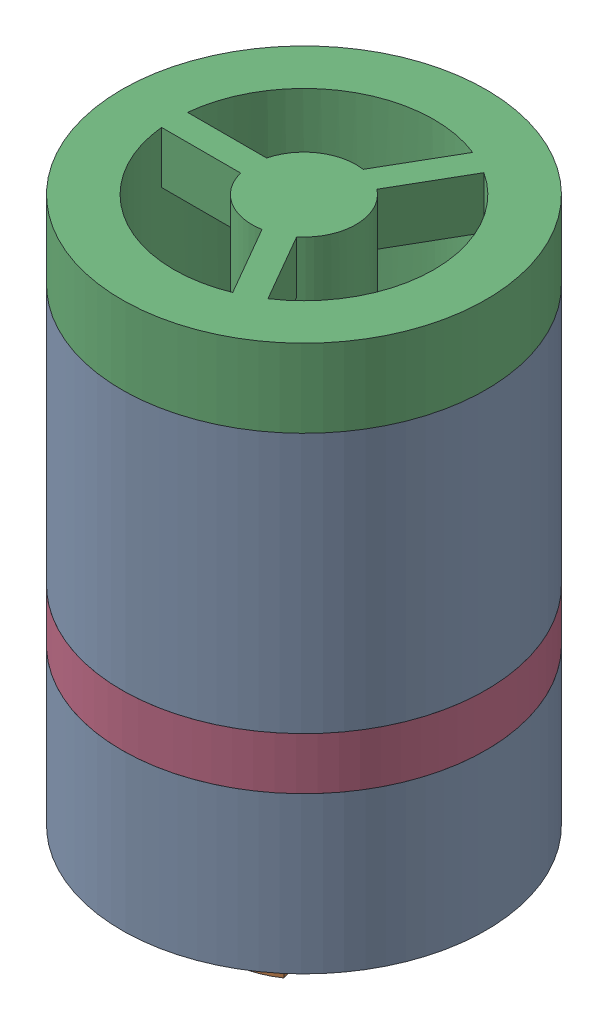
SolidWorks assembly Check valve_2, configuration 默认. Lengths in mm.
Overall size (14 24 14).
4 component instances, 4 part files, 0 mates.
Components (placement in the parent):
- Check valve housing-1: Check valve housing [默认] at origin size (14 18 14)
- Valve-1: Valve [默认] at (0 5 0) x (0.259222 0 0.965818) z (0.965818 0 -0.259222) size (8 11 8)
- Valve lock-1: Valve lock [默认] at (0 13 0) size (14 8 14)
- Seal-1: Seal [默认] at (0 6 0) size (14 2 14)
